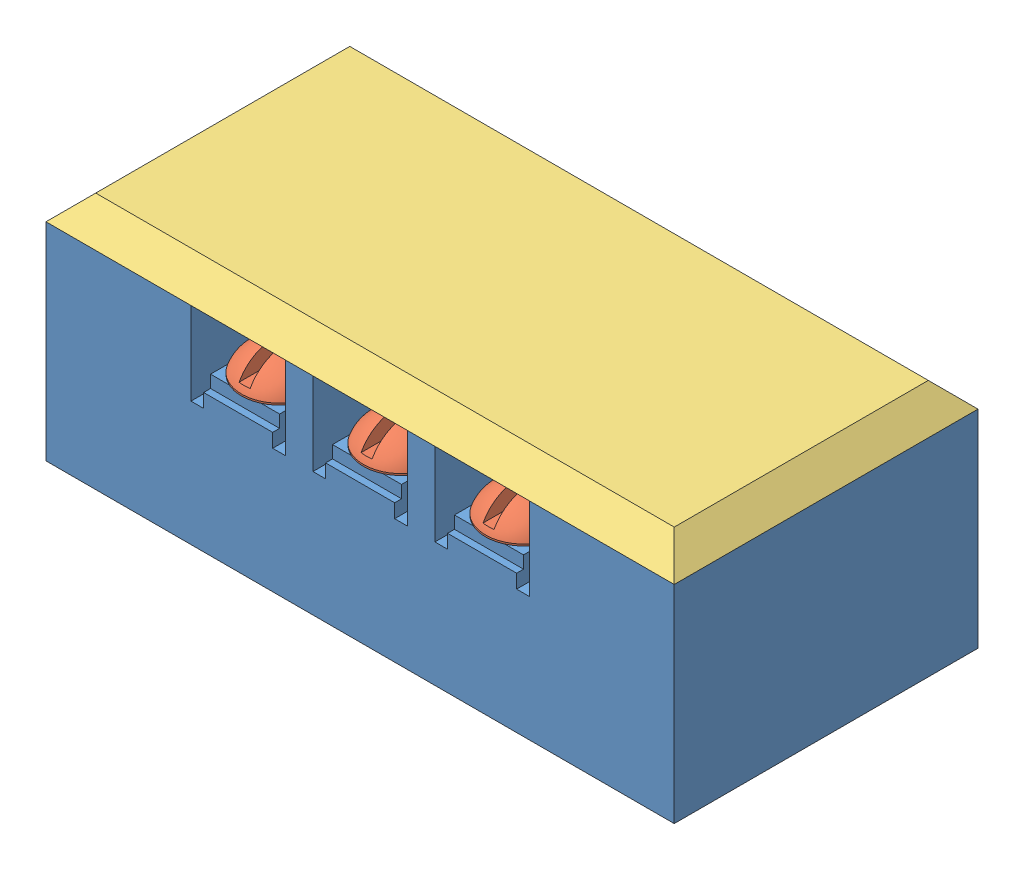
SolidWorks assembly Клеммный блок TB-1503, configuration Default. Lengths in mm.
Overall size (45.5 16.8 22).
8 component instances, 3 part files, 0 mates.
Components (placement in the parent):
- _X2_0414043504420430043B044C_X0_1-1: _X2_0414043504420430043B044C_X0_1 [Default] at (-15.378 -36.07 -20.6359) x (1 0 0) z (0 1 0) size (45.5 22 15)
- _X2_04120438043D0442_X0_ A.M3-6gx3 _X2_0413041E04210422_X0_ 17473-80-1: _X2_04120438043D0442_X0_ A.M3-6gx3 _X2_0413041E04210422_X0_ 17473-80 [Default] at (-15.378 -25.17 -12.6359) size (5.54 5.1 5.53)
- _X2_04120438043D0442_X0_ A.M3-6gx3 _X2_0413041E04210422_X0_ 17473-80-2: _X2_04120438043D0442_X0_ A.M3-6gx3 _X2_0413041E04210422_X0_ 17473-80 [Default] at (-6.5446 -25.17 -12.6359) size (5.54 5.1 5.53)
- _X2_04120438043D0442_X0_ A.M3-6gx3 _X2_0413041E04210422_X0_ 17473-80-3: _X2_04120438043D0442_X0_ A.M3-6gx3 _X2_0413041E04210422_X0_ 17473-80 [Default] at (-15.378 -25.17 -28.6359) size (5.54 5.1 5.53)
- _X2_04120438043D0442_X0_ A.M3-6gx3 _X2_0413041E04210422_X0_ 17473-80-4: _X2_04120438043D0442_X0_ A.M3-6gx3 _X2_0413041E04210422_X0_ 17473-80 [Default] at (-6.5446 -25.17 -28.6359) size (5.54 5.1 5.53)
- _X2_04120438043D0442_X0_ A.M3-6gx3 _X2_0413041E04210422_X0_ 17473-80-5: _X2_04120438043D0442_X0_ A.M3-6gx3 _X2_0413041E04210422_X0_ 17473-80 [Default] at (-24.1631 -25.17 -28.6359) size (5.54 5.1 5.53)
- _X2_04120438043D0442_X0_ A.M3-6gx3 _X2_0413041E04210422_X0_ 17473-80-6: _X2_04120438043D0442_X0_ A.M3-6gx3 _X2_0413041E04210422_X0_ 17473-80 [Default] at (-24.2113 -25.17 -12.6359) size (5.54 5.1 5.53)
- _X2_0414043504420430043B044C_X0_2-1: _X2_0414043504420430043B044C_X0_2 [Default] at (-15.378 -21.07 -20.6359) x (0 0 1) z (-1 0 0) size (22 5.3 45.5)
